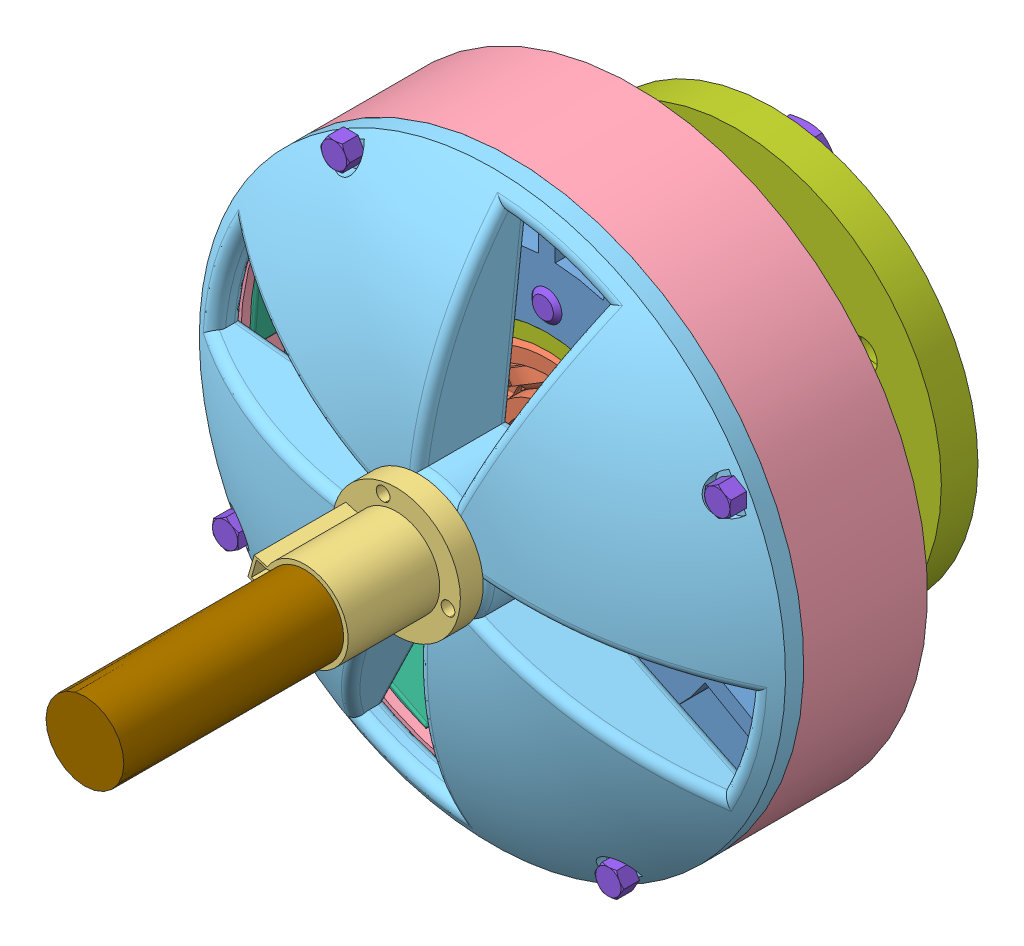
SolidWorks assembly Assem2, configuration Default. Lengths in mm.
Overall size (161.49 161.51 158).
31 component instances, 9 part files, 25 mates.
Components (placement in the parent):
- Stator_1, solid-1: Stator_1, solid [Default] at (0 0 49.148) x (0.766044 0.642788 0) z (0 0 -1) size (114.57 114.7 22.1)
- Bearing 303 ГОСТ 8338-75-1: Bearing 303 ГОСТ 8338-75 [По умолчанию] at (0 0 42.148) x (0 0 -1) z (0.852675 0.522442 0) size (14 47 47)
- Bearing 303 ГОСТ 8338-75-2: Bearing 303 ГОСТ 8338-75 [По умолчанию] at (0 0 7) x (0 0 -1) z (0.643788 -0.765203 0) size (14 47 47)
- Rotor-shaft holder-1: Rotor-shaft holder [Default] at (0 0 77.024) x (-0.273498 -0.961873 0) z (0 0 1) size (28 28 25)
- rotor 1.3 cylinder-1: rotor 1.3 cylinder [Default] at (0 0 30.024) x (0 0 1) z (0.951715 0.306983 0) size (27 128 128)
- rotor cap-1: rotor cap [Default] at (0 0 57.024) x (-0.273498 -0.961873 0) z (-0.961873 0.273498 0) size (128 24.12 128)
- 25x14x2.5mm magnet-1: 25x14x2.5mm magnet [Default] at (-52.957 27.1257 42.524) x (0 0 1) z (0.890034 -0.455895 0) size (25 14 1.5)
- 25x14x2.5mm magnet-2: 25x14x2.5mm magnet [Default] at (-38.5453 45.3267 42.524) x (0 0 1) z (0.647821 -0.761793 0) size (25 14 1.5)
- 25x14x2.5mm magnet-3: 25x14x2.5mm magnet [Default] at (-18.2655 56.627 42.524) x (0 0 1) z (0.306983 -0.951715 0) size (25 14 1.5)
- 25x14x2.5mm magnet-4: 25x14x2.5mm magnet [Default] at (4.7951 59.3065 42.524) x (0 0 1) z (-0.080591 -0.996747 0) size (25 14 1.5)
- 25x14x2.5mm magnet-5: 25x14x2.5mm magnet [Default] at (27.1257 52.957 42.524) x (0 0 1) z (-0.455895 -0.890034 0) size (25 14 1.5)
- 25x14x2.5mm magnet-6: 25x14x2.5mm magnet [Default] at (45.3267 38.5453 42.524) x (0 0 1) z (-0.761793 -0.647821 0) size (25 14 1.5)
- 25x14x2.5mm magnet-7: 25x14x2.5mm magnet [Default] at (56.627 18.2655 42.524) x (0 0 1) z (-0.951715 -0.306983 0) size (25 14 1.5)
- 25x14x2.5mm magnet-8: 25x14x2.5mm magnet [Default] at (59.3065 -4.7951 42.524) x (0 0 1) z (-0.996747 0.080591 0) size (25 14 1.5)
- 25x14x2.5mm magnet-9: 25x14x2.5mm magnet [Default] at (52.957 -27.1257 42.524) x (0 0 1) z (-0.890034 0.455895 0) size (25 14 1.5)
- 25x14x2.5mm magnet-10: 25x14x2.5mm magnet [Default] at (38.5453 -45.3267 42.524) x (0 0 1) z (-0.647821 0.761793 0) size (25 14 1.5)
- 25x14x2.5mm magnet-11: 25x14x2.5mm magnet [Default] at (18.2655 -56.627 42.524) x (0 0 1) z (-0.306983 0.951715 0) size (25 14 1.5)
- 25x14x2.5mm magnet-12: 25x14x2.5mm magnet [Default] at (-4.7951 -59.3065 42.524) x (0 0 1) z (0.080591 0.996747 0) size (25 14 1.5)
- 25x14x2.5mm magnet-13: 25x14x2.5mm magnet [Default] at (-27.1257 -52.957 42.524) x (0 0 1) z (0.455895 0.890034 0) size (25 14 1.5)
- 25x14x2.5mm magnet-14: 25x14x2.5mm magnet [Default] at (-45.3267 -38.5453 42.524) x (0 0 1) z (0.761793 0.647821 0) size (25 14 1.5)
- 25x14x2.5mm magnet-15: 25x14x2.5mm magnet [Default] at (-56.627 -18.2655 42.524) x (0 0 1) z (0.951715 0.306983 0) size (25 14 1.5)
- 25x14x2.5mm magnet-16: 25x14x2.5mm magnet [Default] at (-59.3065 4.7951 42.524) x (0 0 1) z (0.996747 -0.080591 0) size (25 14 1.5)
- Bearing Hub holes-2: Bearing Hub holes [Default] at origin size (90 90 49.15)
- Bold-1: Bold [Default] at (27.7128 -16 0) x (1 0 0) z (0 1 0) size (14 58 12.12)
- Bold-2: Bold [Default] at (-27.7128 -16 0) x (-0.5 -0.866025 0) z (0.866025 -0.5 0) size (14 58 12.12)
- Bold-3: Bold [Default] at (0 32 0) x (-0.5 0.866025 0) z (-0.866025 -0.5 0) size (14 58 12.12)
- shaft-2: shaft [Default] x (0.273498 0.961873 0) z (0.961873 -0.273498 0) size (17 150 20)
- Bold-7: Bold [3mm] at (53.7228 29.9354 69.0906) x (0 1 0) z (1 0 0) size (6.36 26.36 5.51)
- Bold-8: Bold [3mm] at (29.9354 -53.7228 69.0906) x (1 0 0) z (0 -1 0) size (6.36 26.36 5.51)
- Bold-9: Bold [3mm] at (-53.7228 -29.9354 69.0906) x (0 -1 0) z (-1 0 0) size (6.36 26.36 5.51)
- Bold-10: Bold [3mm] at (-29.9354 53.7228 69.0906) x (-1 0 0) z (0 1 0) size (6.36 26.36 5.51)
Mates (geometry in assembly coordinates):
- Coincident6: coincident anti-aligned: plane of rotor 1.3 cylinder-1 through (-56.1483 20.8955 55.024) normal (0.890034 -0.455895 0); plane of 25x14x2.5mm magnet-1 through (-52.957 27.1257 42.524) normal (-0.890034 0.455895 0)
- Coincident7: coincident anti-aligned: plane of rotor 1.3 cylinder-1 through (3.1913 6.2302 55.024) normal (-0.455895 -0.890034 0); plane of 25x14x2.5mm magnet-1 through (-48.4307 32.6721 55.024) normal (0.455895 0.890034 0)
- Coincident8: coincident anti-aligned: plane of rotor 1.3 cylinder-1 through (0 0 55.024) normal (0 0 -1); plane of 25x14x2.5mm magnet-1 through (-48.4307 32.6721 55.024) normal (0 0 1)
- Concentric21: concentric anti-aligned: cylinder of rotor 1.3 cylinder-1 through (-29.9354 53.7226 57.024) axis (0 0 -1) radius 1.5; cylinder of rotor cap-1 through (-29.9354 53.7226 77.024) axis (0 0 1) radius 1.5
- Concentric22: concentric aligned: cylinder of Bearing 303 ГОСТ 8338-75-1 through (0 0 35.148) axis (0 0 -1) radius 23.5; cylinder of Bearing Hub holes-2 through (0 0 49.148) axis (0 0 -1) radius 26.9
- Coincident12: coincident aligned: plane of Bearing 303 ГОСТ 8338-75-2 through (0 0 0) normal (0 0 -1); plane of Bearing Hub holes-2 through (0 0 0) normal (0 0 -1)
- Coincident16: coincident aligned: plane of Stator_1, solid-1 through (0 0 49.148) normal (0 0 1); plane of Bearing Hub holes-2 through (0 0 49.148) normal (0 0 1)
- Coincident17: coincident anti-aligned: plane of rotor 1.3 cylinder-1 through (0 0 57.024) normal (0 0 1); plane of rotor cap-1 through (8.1759 -2.3247 57.024) normal (0 0 -1)
- Coincident18: coincident aligned: plane of Stator_1, solid-1 through (0 0 30.024) normal (0 0 -1); plane of rotor 1.3 cylinder-1 through (0 0 30.024) normal (0 0 -1)
- Coincident19: coincident anti-aligned: plane of Rotor-shaft holder-1 through (0 0 77.024) normal (0 0 -1); plane of rotor cap-1 through (12.5043 -3.5555 77.024) normal (0 0 1)
- Concentric23: concentric aligned: cylinder of Stator_1, solid-1 through (27.7128 -16 50) axis (0 0 -1) radius 3.3; cylinder of Bearing Hub holes-2 through (27.7128 -16 0) axis (0 0 -1) radius 3.3
- Coincident22: coincident anti-aligned: plane of Bearing Hub holes-2 through (0 0 0) normal (0 0 -1); plane of Bold-1 through (20.7128 -16 0) normal (0 0 1)
- Concentric25: concentric aligned: cylinder of Bearing Hub holes-2 through (27.7128 -16 0) axis (0 0 -1) radius 3.3; cylinder of Bold-1 through (27.7128 -16 50) axis (0 0 -1) radius 3.3
- Concentric29: concentric aligned: cylinder of Bearing 303 ГОСТ 8338-75-2 through (0 0 0) axis (0 0 -1) radius 8.5; cylinder of shaft-2 through (0 0 150) axis (0 0 -1) radius 8.5
- Coincident25: coincident aligned: plane of Bearing Hub holes-2 through (0 0 0) normal (0 0 -1); plane of shaft-2 through (0 0 0) normal (0 0 -1)
- Concentric30: concentric aligned: cylinder of Rotor-shaft holder-1 through (-2.8679 11.3946 77.024) axis (0 0 1) radius 1.5; cylinder of rotor cap-1 through (-2.8679 11.3946 56.8395) axis (0 0 1) radius 1.5
- Concentric31: concentric anti-aligned: cylinder of Rotor-shaft holder-1 through (0 0 77.024) axis (0 0 1) radius 8.5; cylinder of shaft-2 through (0 0 150) axis (0 0 -1) radius 8.5
- Concentric32: concentric aligned: cylinder of rotor cap-1 through (0 0 25.7164) axis (0 0 -1) radius 64; cylinder of shaft-2 through (0 0 150) axis (0 0 -1) radius 8.5
- Coincident26: coincident anti-aligned: plane of Rotor-shaft holder-1 through (-0.547 -1.9237 77.024) normal (0.273498 0.961873 0); plane of shaft-2 through (-0.547 -1.9237 97.02) normal (-0.273498 -0.961873 0)
- Concentric33: concentric aligned: cylinder of Bearing 303 ГОСТ 8338-75-1 through (0 0 35.148) axis (0 0 -1) radius 8.5; cylinder of shaft-2 through (0 0 150) axis (0 0 -1) radius 8.5
- Concentric34: concentric anti-aligned: circle of Bearing Hub holes-2; cylinder of shaft-2 through (0 0 150) axis (0 0 -1) radius 8.5
- Concentric35: concentric aligned: cylinder of rotor 1.3 cylinder-1 through (0 0 57.024) axis (0 0 -1) radius 64; cylinder of shaft-2 through (0 0 150) axis (0 0 -1) radius 8.5
- Concentric36: concentric aligned: cylinder of rotor 1.3 cylinder-1 through (0 0 57.024) axis (0 0 -1) radius 64; cylinder of rotor cap-1 through (0 0 25.7164) axis (0 0 -1) radius 64
- Concentric37: concentric aligned: cylinder of rotor cap-1 through (53.7226 29.9354 77.024) axis (0 0 1) radius 1.5; cylinder of Bold-7 through (53.7226 29.9354 39.2967) axis (0 0 1) radius 1.5
- Coincident27: coincident anti-aligned: plane of rotor cap-1 through (53.3124 28.4926 62.024) normal (0 0 1); plane of Bold-7 through (53.7226 26.7536 62.024) normal (0 0 -1)
